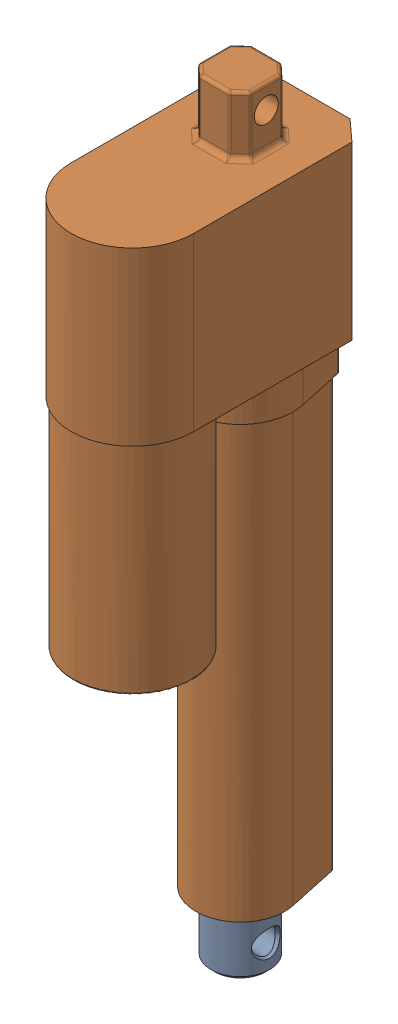
SolidWorks assembly HDA4 Assembly v2, configuration Default. Lengths in mm.
Overall size (41.86 263.14 81.57).
2 component instances, 2 part files, 0 mates.
Components (placement in the parent):
- HDA4 shaft-1: HDA4 shaft [Default] at (-339.725 6758.3553 2877.4102) x (0 -0.000053 1) z (1 0 0) size (19.96 184.32 19.97)
- HDA4-1: HDA4 [Default] at (-339.725 6817.1951 2914.256) x (-1 0 0) z (0 -0.000053 1) size (41.86 241.97 81.56)
